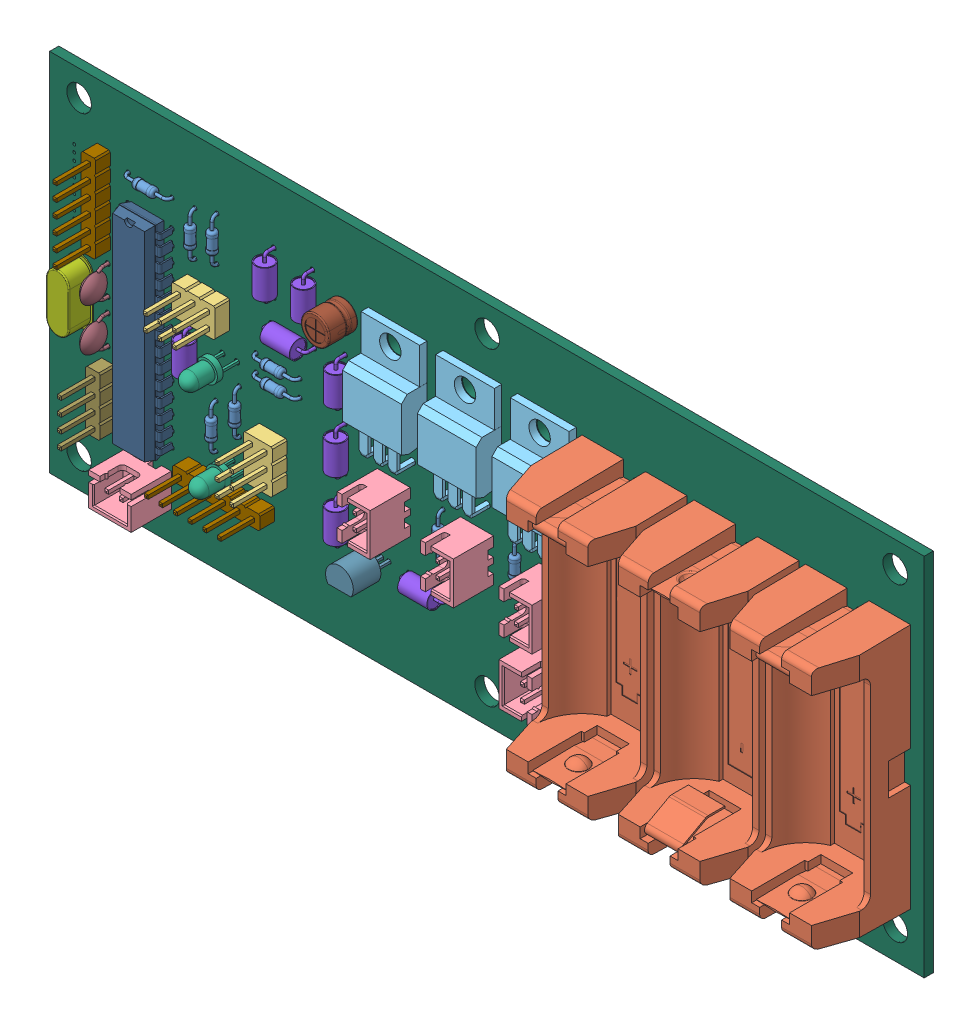
SolidWorks assembly cut down control board, configuration Default. Lengths in mm.
Overall size (152.42 63.66 22.84).
84 component instances, 15 part files, 0 mates.
Components (placement in the parent):
- cut down control board.step-1: cut down control board.step [Default] at origin size (152.42 63.66 22.84)
  - R_Axial_DIN0204_L3.6mm_D1.6mm_P7.62mm_Horizontal.step-1: R_Axial_DIN0204_L3.6mm_D1.6mm_P7.62mm_Horizontal.step [Default] at (157.48 -100.33 1.65) x (0 -1 0) z (0 0 1) size (8.12 1.6 4.72)
    - SOLID.step-1: SOLID.step [Default] at origin size (8.12 1.6 4.72)
  - keystone-PN1051.step-1: keystone-PN1051.step [Default] at (197.3203 -97.6461 11.15) x (0 -1 0) z (-1 0 0) size (45.62 19.87 18.3)
    - COMPOUND.step-1: COMPOUND.step [Default] at origin size (45.62 19.87 18.3)
  - R_Axial_DIN0204_L3.6mm_D1.6mm_P7.62mm_Horizontal.step-2: R_Axial_DIN0204_L3.6mm_D1.6mm_P7.62mm_Horizontal.step [Default] at (100.9065 -86.4283 1.65) x (0 1 0) z (0 0 1) size (8.12 1.6 4.72)
    - SOLID.step-1: SOLID.step [Default] at origin size (8.12 1.6 4.72)
  - PinHeader_2x03_P2.54mm_Vertical.step-1: PinHeader_2x03_P2.54mm_Vertical.step [Default] at (105.7328 -90.6349 1.65) x (0 -1 0) z (0 0 1) size (5.08 7.62 11.54)
    - SOLID-0.step-1: SOLID-0.step [Default] at origin size (5.08 7.62 11.54)
  - JST_XH_B2B-XH-A_1x02_P2.50mm_Vertical.step-1: JST_XH_B2B-XH-A_1x02_P2.50mm_Vertical.step [Default] at (164.3519 -115.8176 1.65) x (0 -1 0) z (0 0 1) size (7.4 5.75 10.4)
    - SOLID-1.step-1: SOLID-1.step [Default] at origin size (7.4 5.75 10.4)
  - TO-220-3_Horizontal_TabDown.step-1: TO-220-3_Horizontal_TabDown.step [Default] at (146.7568 -98.0842 1.65) size (10.25 19.74 10.78)
    - SOLID-2.step-1: SOLID-2.step [Default] at origin size (10.25 19.74 10.78)
  - LED_D3.0mm.step-1: LED_D3.0mm.step [Default] at (110.0021 -113.6003 1.65) x (-1 0 0) z (0 0 1) size (4.91 11.09 10.81)
    - SOLID-3.step-1: SOLID-3.step [Default] at origin size (4.91 11.09 10.81)
  - Crystal_HC49-4H_Vertical.step-1: Crystal_HC49-4H_Vertical.step [Default] at (81.0965 -103.4422 1.65) x (0 1 0) z (0 0 1) size (11.05 4.65 7)
    - SOLID-4.step-1: SOLID-4.step [Default] at origin size (11.05 4.65 7)
  - R_Axial_DIN0204_L3.6mm_D1.6mm_P7.62mm_Horizontal.step-3: R_Axial_DIN0204_L3.6mm_D1.6mm_P7.62mm_Horizontal.step [Default] at (144.1601 -102.6406 1.65) x (0 -1 0) z (0 0 1) size (8.12 1.6 4.72)
    - SOLID.step-1: SOLID.step [Default] at origin size (8.12 1.6 4.72)
  - R_Axial_DIN0204_L3.6mm_D1.6mm_P7.62mm_Horizontal.step-4: R_Axial_DIN0204_L3.6mm_D1.6mm_P7.62mm_Horizontal.step [Default] at (119.2221 -98.2551 1.65) x (-1 0 0) z (0 0 1) size (8.12 1.6 4.72)
    - SOLID.step-1: SOLID.step [Default] at origin size (8.12 1.6 4.72)
  - TO-220-3_Horizontal_TabDown.step-2: TO-220-3_Horizontal_TabDown.step [Default] at (133.7299 -98.0842 1.65) size (10.25 19.74 10.78)
    - SOLID-2.step-1: SOLID-2.step [Default] at origin size (10.25 19.74 10.78)
  - TO-220-3_Horizontal_TabDown.step-3: TO-220-3_Horizontal_TabDown.step [Default] at (159.7537 -98.0842 1.65) size (10.25 19.74 10.78)
    - SOLID-2.step-1: SOLID-2.step [Default] at origin size (10.25 19.74 10.78)
  - C_Axial_L5.1mm_D3.1mm_P7.50mm_Horizontal.step-1: C_Axial_L5.1mm_D3.1mm_P7.50mm_Horizontal.step [Default] at (121.3939 -85.3594 1.65) x (0 1 0) z (0 0 1) size (8.08 3.1 5.34)
    - SOLID-5.step-1: SOLID-5.step [Default] at origin size (8.08 3.1 5.34)
  - R_Axial_DIN0204_L3.6mm_D1.6mm_P7.62mm_Horizontal.step-5: R_Axial_DIN0204_L3.6mm_D1.6mm_P7.62mm_Horizontal.step [Default] at (104.5837 -106.0073 1.65) x (0 -1 0) z (0 0 1) size (8.12 1.6 4.72)
    - SOLID.step-1: SOLID.step [Default] at origin size (8.12 1.6 4.72)
  - keystone-PN1051.step-2: keystone-PN1051.step [Default] at (177.7453 -103.4492 11.15) x (0 1 0) z (1 0 0) size (45.62 19.87 18.3)
    - COMPOUND.step-1: COMPOUND.step [Default] at origin size (45.62 19.87 18.3)
  - C_Axial_L5.1mm_D3.1mm_P7.50mm_Horizontal.step-2: C_Axial_L5.1mm_D3.1mm_P7.50mm_Horizontal.step [Default] at (127.0573 -116.1061 1.65) x (0 1 0) z (0 0 1) size (8.08 3.1 5.34)
    - SOLID-5.step-1: SOLID-5.step [Default] at origin size (8.08 3.1 5.34)
  - PinHeader_1x06_P2.54mm_Vertical.step-1: PinHeader_1x06_P2.54mm_Vertical.step [Default] at (84.9393 -91.4195 1.65) x (-1 0 0) z (0 0 1) size (2.54 15.24 11.54)
    - SOLID-6.step-1: SOLID-6.step [Default] at origin size (2.54 15.24 11.54)
  - C_Axial_L5.1mm_D3.1mm_P7.50mm_Horizontal.step-3: C_Axial_L5.1mm_D3.1mm_P7.50mm_Horizontal.step [Default] at (100.6439 -104.172 1.65) x (0 1 0) z (0 0 1) size (8.08 3.1 5.34)
    - SOLID-5.step-1: SOLID-5.step [Default] at origin size (8.08 3.1 5.34)
  - JST_XH_B2B-XH-A_1x02_P2.50mm_Vertical.step-2: JST_XH_B2B-XH-A_1x02_P2.50mm_Vertical.step [Default] at (149.6 -107.1392 1.65) x (0 1 0) z (0 0 1) size (7.4 5.75 10.4)
    - SOLID-1.step-1: SOLID-1.step [Default] at origin size (7.4 5.75 10.4)
  - R_Axial_DIN0204_L3.6mm_D1.6mm_P7.62mm_Horizontal.step-6: R_Axial_DIN0204_L3.6mm_D1.6mm_P7.62mm_Horizontal.step [Default] at (96.9299 -79.2074 1.65) x (-1 0 0) z (0 0 1) size (8.12 1.6 4.72)
    - SOLID.step-1: SOLID.step [Default] at origin size (8.12 1.6 4.72)
  - C_Axial_L5.1mm_D3.1mm_P7.50mm_Horizontal.step-4: C_Axial_L5.1mm_D3.1mm_P7.50mm_Horizontal.step [Default] at (127.0512 -105.7136 1.65) x (0 1 0) z (0 0 1) size (8.08 3.1 5.34)
    - SOLID-5.step-1: SOLID-5.step [Default] at origin size (8.08 3.1 5.34)
  - PinHeader_2x03_P2.54mm_Vertical.step-2: PinHeader_2x03_P2.54mm_Vertical.step [Default] at (113.1992 -106.8789 1.65) size (5.08 7.62 11.54)
    - SOLID-0.step-1: SOLID-0.step [Default] at origin size (5.08 7.62 11.54)
  - JST_XH_B2B-XH-A_1x02_P2.50mm_Vertical.step-3: JST_XH_B2B-XH-A_1x02_P2.50mm_Vertical.step [Default] at (91.8947 -122.8628 1.65) size (7.4 5.75 10.4)
    - SOLID-1.step-1: SOLID-1.step [Default] at origin size (7.4 5.75 10.4)
  - R_Axial_DIN0204_L3.6mm_D1.6mm_P7.62mm_Horizontal.step-7: R_Axial_DIN0204_L3.6mm_D1.6mm_P7.62mm_Horizontal.step [Default] at (111.5886 -95.3454 1.65) size (8.12 1.6 4.72)
    - SOLID.step-1: SOLID.step [Default] at origin size (8.12 1.6 4.72)
  - LED_D3.0mm.step-2: LED_D3.0mm.step [Default] at (105.7028 -98.3315 1.65) size (4.91 11.09 10.81)
    - SOLID-3.step-1: SOLID-3.step [Default] at origin size (4.91 11.09 10.81)
  - DIP-28_W7.62mm.step-1: DIP-28_W7.62mm.step [Default] at (89.2658 -83.8859 1.65) size (7.87 35.56 6.98)
    - SOLID-7.step-1: SOLID-7.step [Default] at origin size (7.87 35.56 6.98)
  - CP_Radial_D5.0mm_P2.00mm.step-1: CP_Radial_D5.0mm_P2.00mm.step [Default] at (125.8996 -81.746 1.65) size (6.82 7.94 7)
    - SOLID-8.step-1: SOLID-8.step [Default] at origin size (6.82 7.94 7)
  - R_Axial_DIN0204_L3.6mm_D1.6mm_P7.62mm_Horizontal.step-8: R_Axial_DIN0204_L3.6mm_D1.6mm_P7.62mm_Horizontal.step [Default] at (104.7547 -85.2927 1.65) x (0 1 0) z (0 0 1) size (8.12 1.6 4.72)
    - SOLID.step-1: SOLID.step [Default] at origin size (8.12 1.6 4.72)
  - C_Axial_L5.1mm_D3.1mm_P7.50mm_Horizontal.step-5: C_Axial_L5.1mm_D3.1mm_P7.50mm_Horizontal.step [Default] at (114.6695 -85.3936 1.65) x (0 1 0) z (0 0 1) size (8.08 3.1 5.34)
    - SOLID-5.step-1: SOLID-5.step [Default] at origin size (8.08 3.1 5.34)
  - JST_XH_B2B-XH-A_1x02_P2.50mm_Vertical.step-4: JST_XH_B2B-XH-A_1x02_P2.50mm_Vertical.step [Default] at (163.3019 -107.261 1.65) x (0 1 0) z (0 0 1) size (7.4 5.75 10.4)
    - SOLID-1.step-1: SOLID-1.step [Default] at origin size (7.4 5.75 10.4)
  - C_Axial_L5.1mm_D3.1mm_P7.50mm_Horizontal.step-6: C_Axial_L5.1mm_D3.1mm_P7.50mm_Horizontal.step [Default] at (145.6882 -115.2459 1.65) x (-1 0 0) z (0 0 1) size (8.08 3.1 5.34)
    - SOLID-5.step-1: SOLID-5.step [Default] at origin size (8.08 3.1 5.34)
  - PinHeader_1x06_P2.54mm_Vertical.step-2: PinHeader_1x06_P2.54mm_Vertical.step [Default] at (113.5687 -118.0918 1.65) x (0 -1 0) z (0 0 1) size (2.54 15.24 11.54)
    - SOLID-6.step-1: SOLID-6.step [Default] at origin size (2.54 15.24 11.54)
  - PinHeader_1x04_P2.54mm_Vertical.step-1: PinHeader_1x04_P2.54mm_Vertical.step [Default] at (85.7236 -118.3619 1.65) x (-1 0 0) z (0 0 1) size (2.54 10.16 11.54)
    - SOLID-9.step-1: SOLID-9.step [Default] at origin size (2.54 10.16 11.54)
  - C_Axial_L5.1mm_D3.1mm_P7.50mm_Horizontal.step-7: C_Axial_L5.1mm_D3.1mm_P7.50mm_Horizontal.step [Default] at (114.2134 -89.5285 1.65) size (8.08 3.1 5.34)
    - SOLID-5.step-1: SOLID-5.step [Default] at origin size (8.08 3.1 5.34)
  - JST_XH_B2B-XH-A_1x02_P2.50mm_Vertical.step-5: JST_XH_B2B-XH-A_1x02_P2.50mm_Vertical.step [Default] at (135.0886 -107.0981 1.65) x (0 1 0) z (0 0 1) size (7.4 5.75 10.4)
    - SOLID-1.step-1: SOLID-1.step [Default] at origin size (7.4 5.75 10.4)
  - R_Axial_DIN0204_L3.6mm_D1.6mm_P7.62mm_Horizontal.step-9: R_Axial_DIN0204_L3.6mm_D1.6mm_P7.62mm_Horizontal.step [Default] at (108.6679 -109.4233 1.65) x (0 1 0) z (0 0 1) size (8.12 1.6 4.72)
    - SOLID.step-1: SOLID.step [Default] at origin size (8.12 1.6 4.72)
  - C_Axial_L5.1mm_D3.1mm_P7.50mm_Horizontal.step-8: C_Axial_L5.1mm_D3.1mm_P7.50mm_Horizontal.step [Default] at (127.0785 -87.8594 1.65) x (0 -1 0) z (0 0 1) size (8.08 3.1 5.34)
    - SOLID-5.step-1: SOLID-5.step [Default] at origin size (8.08 3.1 5.34)
  - keystone-PN1051.step-3: keystone-PN1051.step [Default] at (216.7078 -103.4492 11.15) x (0 1 0) z (1 0 0) size (45.62 19.87 18.3)
    - COMPOUND.step-1: COMPOUND.step [Default] at origin size (45.62 19.87 18.3)
  - C_Disc_D4.7mm_W2.5mm_P5.00mm.step-1: C_Disc_D4.7mm_W2.5mm_P5.00mm.step [Default] at (85.728 -102.2108 1.65) x (0 -1 0) z (0 0 1) size (5.58 2.5 7.16)
    - SOLID-10.step-1: SOLID-10.step [Default] at origin size (5.58 2.5 7.16)
  - TO-92_Inline.step-1: TO-92_Inline.step [Default] at (132.1735 -115.2285 1.65) size (5.62 3.75 9.8)
    - SOLID-11.step-1: SOLID-11.step [Default] at origin size (5.62 3.75 9.8)
  - C_Disc_D4.7mm_W2.5mm_P5.00mm.step-2: C_Disc_D4.7mm_W2.5mm_P5.00mm.step [Default] at (85.7164 -99.7385 1.65) x (0 1 0) z (0 0 1) size (5.58 2.5 7.16)
    - SOLID-10.step-1: SOLID-10.step [Default] at origin size (5.58 2.5 7.16)
  - cut down control board PCB.step-1: cut down control board PCB.step [Default] at origin size (152.42 63.66 1.6)
